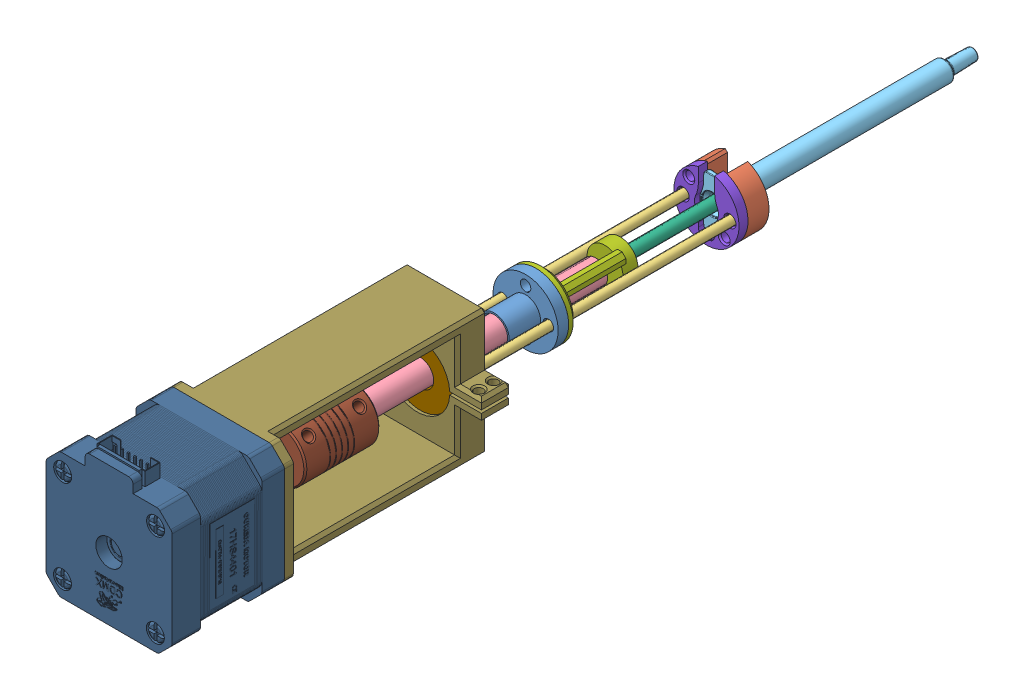
SolidWorks assembly Co_cau_nho_giot_2, configuration Default. Lengths in mm.
Overall size (42.9 46.77 288.22).
15 component instances, 14 part files, 34 mates.
Components (placement in the parent):
- Dai-oc-Vit-me-2: Dai-oc-Vit-me [Default] at (4.5651 -0.5781 49.6755) size (21.7 21.7 15)
- gia-2-truc-3mm-1: gia-2-truc-3mm [Default] at (4.5651 -0.5781 -16.1682) size (21.7 21.03 7)
- truc_3mm_10cm-4: truc_3mm_10cm [Default] at (12.3651 -0.5781 -13.6682) x (-0.346447 0.938069 0) z (0.938069 0.346447 0) size (3 100 3)
- truc_3mm_10cm-5: truc_3mm_10cm [Default] at (-3.2349 -0.5781 -13.6682) x (-0.346447 0.938069 0) z (0.938069 0.346447 0) size (3 100 3)
- truc-vit-me-8mm-1: truc-vit-me-8mm [Default] at (4.5651 -0.5781 130.6532) x (0.404094 0.914717 0) z (-0.914717 0.404094 0) size (8 100 8)
- xi_lanh_ong_chich-1: xi_lanh_ong_chich [Default] at (4.5651 -0.5781 -7.9682) x (0 -1 0) z (-1 0 0) size (17 87 10.2)
- bit_tong_ong_tiem-1: bit_tong_ong_tiem [Default] at (4.5651 -0.5781 14.0002) x (0.418589 0.908176 0) z (0.908176 -0.418589 0) size (10.2 89.28 10.2)
- mieng_day_ong_chich-1: mieng_day_ong_chich [Default] at (4.5651 -0.5781 50.6755) x (-1 0 0) z (0 0 -1) size (21.7 21.7 28)
- Part7^Co_cau_nho_giot_2-1: Part7^Co_cau_nho_giot_2 [Default] at (4.5651 -0.5781 -9.1682) (virtual)
- KEP_ONG_CHICH^Co_cau_nho_giot_2-1: KEP_ONG_CHICH^Co_cau_nho_giot_2 [Default] at (4.5651 -0.5781 -9.1682) size (21.7 21.35 3) (virtual)
- Part12^Co_cau_nho_giot_2-1: Part12^Co_cau_nho_giot_2 [Default] at origin (virtual)
- GIA_DO_TRU_3MM_DC-1: GIA_DO_TRU_3MM_DC [Default] at (4.5651 -0.5789 82.3318) x (1 -0.000104 0) z (0 0 1) size (21.7 21.7 7.01)
- Nema 17 Motor a Pasos 17HS4401-2: Nema 17 Motor a Pasos 17HS4401 [Default] at (4.5651 -0.5781 193.1532) x (0.999999 -0.001585 0) z (0 0 -1) size (42.2 46.7 62.65)
- 8mm_to 5mm_kaplin-1: 8mm_to 5mm_kaplin [Varsayılan] at (4.5651 -0.5781 129.6532) x (0.729719 -0.683747 0) z (-0.683747 -0.729719 0) size (18.93 25 18.11)
- Gia_Dong_co-1: Gia_Dong_co [Default] at (4.5651 -0.5781 155.6532) x (0.999999 -0.001585 0) z (0 0 -1) size (42.83 42 75.32)
Mates (geometry in assembly coordinates):
- Concentric21: concentric anti-aligned: cylinder of Dai-oc-Vit-me-2 through (4.5651 -0.5781 50.6755) axis (0 0 1) radius 10.85; cylinder of gia-2-truc-3mm-1 through (4.5651 -0.5781 -9.1682) axis (0 0 -1) radius 10.85
- Tangent9: tangent aligned: cylinder of Dai-oc-Vit-me-2 through (12.1651 -0.5781 38.6755) axis (0 0 1) radius 1.75; cylinder of gia-2-truc-3mm-1 through (12.3651 -0.5781 -9.1682) axis (0 0 -1) radius 1.55
- Coincident11: coincident anti-aligned: plane of gia-2-truc-3mm-1 through (12.3651 -0.5781 -13.6682) normal (0 0 1); plane of truc_3mm_10cm-4 through (12.3651 -0.5781 -13.6682) normal (0 0 -1)
- Concentric23: concentric aligned: cylinder of gia-2-truc-3mm-1 through (12.3651 -0.5781 -9.1682) axis (0 0 -1) radius 1.55; cylinder of truc_3mm_10cm-4 through (12.3651 -0.5781 86.3318) axis (0 0 -1) radius 1.5
- Coincident12: coincident anti-aligned: plane of gia-2-truc-3mm-1 through (-3.2349 -0.5781 -13.6682) normal (0 0 1); plane of truc_3mm_10cm-5 through (-3.2349 -0.5781 -13.6682) normal (0 0 -1)
- Concentric24: concentric aligned: cylinder of gia-2-truc-3mm-1 through (-3.2349 -0.5781 -9.1682) axis (0 0 -1) radius 1.55; cylinder of truc_3mm_10cm-5 through (-3.2349 -0.5781 86.3318) axis (0 0 -1) radius 1.5
- Concentric27: concentric anti-aligned: cylinder of Dai-oc-Vit-me-2 through (4.5651 -0.5781 64.6755) axis (0 0 -1) radius 4.5; cylinder of truc-vit-me-8mm-1 through (4.5651 -0.5781 30.6532) axis (0 0 1) radius 4
- Concentric29: concentric aligned: cylinder of truc-vit-me-8mm-1 through (4.5651 -0.5781 30.6532) axis (0 0 1) radius 4; cylinder of xi_lanh_ong_chich-1 through (4.5651 -0.5781 77.3277) axis (0 0 1) radius 3.35
- Coincident16: coincident anti-aligned: plane of gia-2-truc-3mm-1 through (4.5651 -0.5781 -9.1682) normal (0 0 1); plane of xi_lanh_ong_chich-1 through (5.0428 14.6097 -9.1682) normal (0 0 -1)
- Concentric30: concentric anti-aligned: cylinder of xi_lanh_ong_chich-1 through (4.5651 -0.5781 77.3277) axis (0 0 1) radius 3.35; cylinder of bit_tong_ong_tiem-1 through (4.5651 -0.5781 -61.4245) axis (0 0 -1) radius 1.95
- InPlace3: in place: plane of ? through (4.5651 -0.5781 42.5794) normal (0 0 -1); plane of ? through (0 0 42.5794) normal (0 0 -1); moOrthogonalPlaneRef_w of ? through (4.5651 -0.5781 42.5794) normal (0 0 -1); plane of ? through (0 0 42.5794) normal (0 1 0); plane of ? through (4.5651 -0.5781 42.5794) normal (0 0 -1); plane of ? through (0 0 42.5794) normal (-1 0 0); plane of Dai-oc-Vit-me-2 through (4.5651 -0.5781 50.6755) normal (0 0 -1); unknown of mieng_day_ong_chich-1
- Coincident18: coincident aligned: plane of ?; plane of ?
- Coincident19: coincident aligned: moOrthogonalPlaneRef_w of Dai-oc-Vit-me-2 through (4.5651 -0.5781 50.6755) normal (0 1 0); plane of mieng_day_ong_chich-1 through (4.5651 -0.5781 50.6755) normal (0 1 0)
- Coincident20: coincident anti-aligned: moOrthogonalPlaneRef_w of Dai-oc-Vit-me-2 through (4.5651 -0.5781 50.6755) normal (1 0 0); plane of mieng_day_ong_chich-1 through (4.5651 -0.5781 50.6755) normal (-1 0 0)
- Concentric31: concentric aligned: cylinder of Dai-oc-Vit-me-2 through (4.5651 -0.5781 50.6755) axis (0 0 1) radius 10.85; cylinder of mieng_day_ong_chich-1 through (4.5651 -0.5781 47.6755) axis (0 0 1) radius 10.85
- InPlace4: in place: plane of gia-2-truc-3mm-1 through (4.5651 -0.5781 -9.1682) normal (0 0 1); plane of ? through (0 0 -9.1682) normal (0 0 1); plane of gia-2-truc-3mm-1 through (4.5651 -0.5781 -9.1682) normal (0 0 1); plane of ? through (0 0 -9.1682) normal (0 1 0); plane of gia-2-truc-3mm-1 through (4.5651 -0.5781 -9.1682) normal (0 0 1); plane of ? through (0 0 -9.1682) normal (1 0 0); plane of gia-2-truc-3mm-1 through (4.5651 -0.5781 -9.1682) normal (0 0 1); unknown of ?
- Coincident24: coincident aligned: plane of ?; plane of ?
- Coincident25: coincident aligned: moOrthogonalPlaneRef_w of gia-2-truc-3mm-1 through (4.5651 -0.5781 -9.1682) normal (0 1 0); plane of Part7^Co_cau_nho_giot_1-1 through (4.5651 -0.5781 -9.1682) normal (0 1 0)
- Coincident26: coincident anti-aligned: moOrthogonalPlaneRef_w of gia-2-truc-3mm-1 through (4.5651 -0.5781 -9.1682) normal (-1 0 0); plane of Part7^Co_cau_nho_giot_1-1 through (4.5651 -0.5781 -9.1682) normal (1 0 0)
- InPlace5: in place: plane of gia-2-truc-3mm-1 through (4.5651 -0.5781 -9.1682) normal (0 0 1); plane of ? through (0 0 -9.1682) normal (0 0 1); plane of gia-2-truc-3mm-1 through (4.5651 -0.5781 -9.1682) normal (0 0 1); plane of ? through (0 0 -9.1682) normal (0 1 0); plane of gia-2-truc-3mm-1 through (4.5651 -0.5781 -9.1682) normal (0 0 1); plane of ? through (0 0 -9.1682) normal (1 0 0); plane of gia-2-truc-3mm-1 through (4.5651 -0.5781 -9.1682) normal (0 0 1); unknown of ?
- Coincident27: coincident aligned: plane of ?; plane of ?
- Coincident28: coincident aligned: moOrthogonalPlaneRef_w of gia-2-truc-3mm-1 through (4.5651 -0.5781 -9.1682) normal (0 1 0); plane of KEP_ONG_CHICH^Co_cau_nho_giot_1-1 through (4.5651 -0.5781 -9.1682) normal (0 1 0)
- Coincident29: coincident anti-aligned: moOrthogonalPlaneRef_w of gia-2-truc-3mm-1 through (4.5651 -0.5781 -9.1682) normal (-1 0 0); plane of KEP_ONG_CHICH^Co_cau_nho_giot_1-1 through (4.5651 -0.5781 -9.1682) normal (1 0 0)
- Coincident44: coincident anti-aligned: plane of truc_3mm_10cm-5 through (-3.2349 -0.5781 86.3318) normal (0 0 1); plane of GIA_DO_TRU_3MM_DC-1 through (-3.2349 -0.5781 86.3318) normal (0 0 -1)
- Concentric36: concentric aligned: cylinder of truc_3mm_10cm-5 through (-3.2349 -0.5781 86.3318) axis (0 0 -1) radius 1.5; cylinder of GIA_DO_TRU_3MM_DC-1 through (-3.2349 -0.5781 89.3318) axis (0 0 -1) radius 1.55
- Coincident45: coincident anti-aligned: plane of bit_tong_ong_tiem-1 through (5.6325 1.7377 26.1755) normal (0 0 1); plane of mieng_day_ong_chich-1 through (4.5651 -0.5781 26.1755) normal (0 0 -1)
- Concentric38: concentric anti-aligned: cylinder of truc-vit-me-8mm-1 through (4.5651 -0.5781 30.6532) axis (0 0 1) radius 4; cylinder of Nema 17 Motor a Pasos 17HS4401-2 through (4.5651 -0.5781 155.6532) axis (0 0 -1) radius 2.5
- Concentric39: concentric anti-aligned: cylinder of Nema 17 Motor a Pasos 17HS4401-2 through (4.5651 -0.5781 155.6532) axis (0 0 -1) radius 2.5; cylinder of 8mm_to 5mm_kaplin-1 through (4.5651 -0.5781 130.6532) axis (0 0 1) radius 2.5
- Coincident46: coincident aligned: plane of Nema 17 Motor a Pasos 17HS4401-2 through (4.5651 -0.5781 130.6532) normal (0 0 -1); plane of 8mm_to 5mm_kaplin-1 through (4.5651 -0.5781 130.6532) normal (0 0 -1)
- Coincident47: coincident anti-aligned: plane of truc-vit-me-8mm-1 through (4.5651 -0.5781 130.6532) normal (0 0 1); plane of 8mm_to 5mm_kaplin-1 through (4.5651 -0.5781 130.6532) normal (0 0 -1)
- InPlace11: in place: plane of ? through (4.5651 -0.5781 155.6532) normal (0 0 -1); plane of ? through (0 0 155.6532) normal (0 0 -1); plane of ? through (4.5651 -0.5781 155.6532) normal (0 0 -1); plane of ? through (0 0 155.6532) normal (0 1 0); plane of ? through (4.5651 -0.5781 155.6532) normal (0 0 -1); plane of ? through (0 0 155.6532) normal (-1 0 0); plane of Nema 17 Motor a Pasos 17HS4401-2 through (4.5651 -0.5781 155.6532) normal (0 0 -1); unknown of Gia_Dong_co-1
- Coincident51: coincident aligned: plane of ?; plane of ?
- Coincident52: coincident aligned: moOrthogonalPlaneRef_w of Nema 17 Motor a Pasos 17HS4401-2; plane of Part70^Co_cau_nho_giot_1-1 through (4.5651 -0.5781 155.6532) normal (-0.001585 -0.999999 0)
- Coincident53: coincident anti-aligned: moOrthogonalPlaneRef_w of Nema 17 Motor a Pasos 17HS4401-2; plane of Part70^Co_cau_nho_giot_1-1 through (4.5651 -0.5781 155.6532) normal (0.999999 -0.001585 0)
